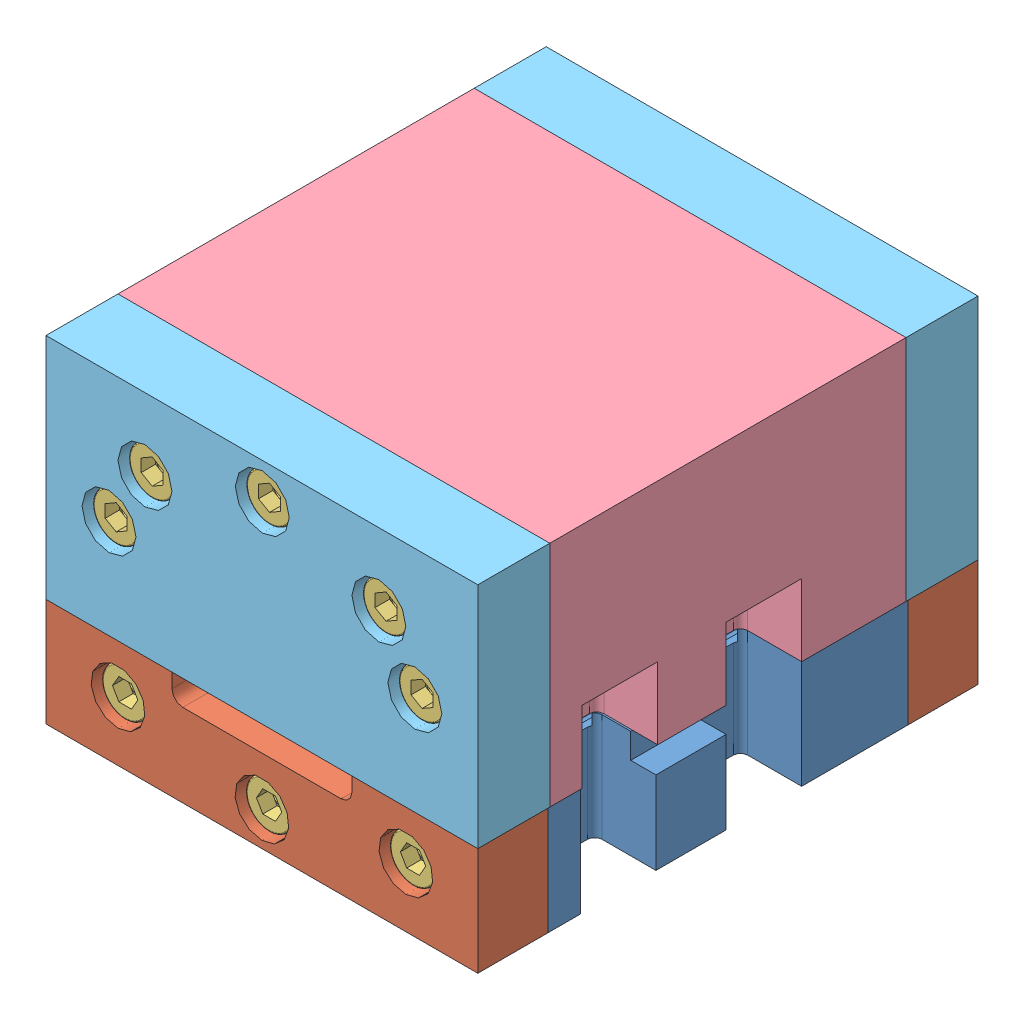
SolidWorks assembly Сборка пресс-формы - МЛИ1.00.00, configuration По умолчанию. Lengths in mm.
Overall size (120 93.5 139).
28 component instances, 7 part files, 4 mates.
Components (placement in the parent):
- Сборка пуансона - МЛИ1.02.00-1: Сборка пуансона - МЛИ1.02.00 [По умолчанию] at (0 0 99.5) x (1 0 0) z (0 1 0) size (120 139 30)
  - Пуансон - МЛИ1.02.01-1: Пуансон - МЛИ1.02.01 [По умолчанию] at origin size (120 100 30)
  - Боковина пуансона - МЛИ1.02.02-1: Боковина пуансона - МЛИ1.02.02 [По умолчанию] at (120 100 -30) x (-1 0 0) z (0 0 -1) size (120 19.5 30)
  - Боковина пуансона - МЛИ1.02.02-3: Боковина пуансона - МЛИ1.02.02 [По умолчанию] at (0 0 -30) x (1 0 0) z (0 0 -1) size (120 19.5 30)
  - socket head cap screw_iso-1: socket head cap screw_iso [ISO 4762 M8 x 16 - 16N] at (100 -17.5 -13.5) x (0 1 0) z (0 0 1) size (24 13 13)
  - socket head cap screw_iso-2: socket head cap screw_iso [ISO 4762 M8 x 16 - 16N] at (60 -17.5 -20.5) x (0 1 0) z (0 0 1) size (24 13 13)
  - socket head cap screw_iso-3: socket head cap screw_iso [ISO 4762 M8 x 16 - 16N] at (20 -17.5 -13.5) x (0 1 0) z (0 0 1) size (24 13 13)
  - socket head cap screw_iso-4: socket head cap screw_iso [ISO 4762 M8 x 16 - 16N] at (20 117.5 -13.5) x (0 -1 0) z (0 0 1) size (24 13 13)
  - socket head cap screw_iso-5: socket head cap screw_iso [ISO 4762 M8 x 16 - 16N] at (60 117.5 -20.5) x (0 -1 0) z (0 0 1) size (24 13 13)
  - socket head cap screw_iso-6: socket head cap screw_iso [ISO 4762 M8 x 16 - 16N] at (100 117.5 -13.5) x (0 -1 0) z (0 0 1) size (24 13 13)
- Сборка матрицы - МЛИ1.01.00-1: Сборка матрицы - МЛИ1.01.00 [По умолчанию] at origin size (120 88.5 139)
  - Матрица - МЛИ1.01.02-1: Матрица - МЛИ1.01.02 [По умолчанию] at origin size (120 63.5 99)
  - Боковина пресс-формы - МЛИ1.01.04-1: Боковина пресс-формы - МЛИ1.01.04 [По умолчанию] at (0 63.5 0) x (0 0 -1) z (-1 0 0) size (20 63.5 120)
  - Боковина пресс-формы - МЛИ1.01.04-2: Боковина пресс-формы - МЛИ1.01.04 [По умолчанию] at (120 63.5 99) x (0 0 1) z (1 0 0) size (20 63.5 120)
  - socket head cap screw_iso-1: socket head cap screw_iso [ISO 4762 M8 x 16 - 16N] at (17.5 27.5 117) x (0 0 -1) z (1 0 0) size (24 13 13)
  - socket head cap screw_iso-2: socket head cap screw_iso [ISO 4762 M8 x 16 - 16N] at (27.5 43.5 117) x (0 0 -1) z (1 0 0) size (24 13 13)
  - socket head cap screw_iso-3: socket head cap screw_iso [ISO 4762 M8 x 16 - 16N] at (60.109 53.5 117) x (0 0 -1) z (1 0 0) size (24 13 13)
  - socket head cap screw_iso-4: socket head cap screw_iso [ISO 4762 M8 x 16 - 16N] at (92.5 43.5 117) x (0 0 -1) z (1 0 0) size (24 13 13)
  - socket head cap screw_iso-5: socket head cap screw_iso [ISO 4762 M8 x 16 - 16N] at (102.5 27.5 117) x (0 0 -1) z (1 0 0) size (24 13 13)
  - socket head cap screw_iso-6: socket head cap screw_iso [ISO 4762 M8 x 16 - 16N] at (102.5 27.5 -18) x (0 0 1) z (-1 0 0) size (24 13 13)
  - socket head cap screw_iso-7: socket head cap screw_iso [ISO 4762 M8 x 16 - 16N] at (92.5 43.5 -18) x (0 0 1) z (-1 0 0) size (24 13 13)
  - socket head cap screw_iso-8: socket head cap screw_iso [ISO 4762 M8 x 16 - 16N] at (59.891 53.5 -18) x (0 0 1) z (-1 0 0) size (24 13 13)
  - socket head cap screw_iso-9: socket head cap screw_iso [ISO 4762 M8 x 16 - 16N] at (27.5 43.5 -18) x (0 0 1) z (-1 0 0) size (24 13 13)
  - socket head cap screw_iso-10: socket head cap screw_iso [ISO 4762 M8 x 16 - 16N] at (17.5 27.5 -18) x (0 0 1) z (-1 0 0) size (24 13 13)
  - Направляющая - МЛИ1.01.01-2: Направляющая - МЛИ1.01.01 [По умолчанию] at (8 30 87) x (0 -1 0) z (0.779572 0 -0.626312) size (55 10 10)
  - Направляющая - МЛИ1.01.01-3: Направляющая - МЛИ1.01.01 [По умолчанию] at (112 30 12) x (0 -1 0) z (-0.854743 0 -0.519052) size (55 10 10)
  - Подставка - МЛИ1.01.03-1: Подставка - МЛИ1.01.03 [По умолчанию] at (60 33.5 76.5) x (0 -1 0) z (-0.902288 0 0.431134) size (36.5 13.89 13.89)
  - Подставка - МЛИ1.01.03-2: Подставка - МЛИ1.01.03 [По умолчанию] at (60 33.5 22.5) x (0 -1 0) z (-0.706159 0 0.708053) size (36.5 13.89 13.89)
Mates (geometry in assembly coordinates):
- Совпадение1: coordinate: point of Сборка матрицы - МЛИ1.01.00-1
- Концентричный26: concentric aligned: cylinder of Сборка пуансона - МЛИ1.02.00-1/Пуансон - МЛИ1.02.01-1 through (8 -30 87) axis (0 1 0) radius 5; cylinder of Сборка матрицы - МЛИ1.01.00-1/Направляющая - МЛИ1.01.01-2 through (8 30 87) axis (0 1 0) radius 5
- Концентричный28: concentric aligned: cylinder of Сборка пуансона - МЛИ1.02.00-1/Пуансон - МЛИ1.02.01-1 through (112 -30 12) axis (0 1 0) radius 5; cylinder of Сборка матрицы - МЛИ1.01.00-1/Направляющая - МЛИ1.01.01-3 through (112 30 12) axis (0 1 0) radius 5
- Граничное расстояние3: limit distance = 0 mm anti-aligned: plane of Сборка пуансона - МЛИ1.02.00-1/Боковина пуансона - МЛИ1.02.02-1 through (120 0 -20) normal (0 1 0); plane of Сборка матрицы - МЛИ1.01.00-1/Боковина пресс-формы - МЛИ1.01.04-1 through (0 0 -20) normal (0 -1 0)
